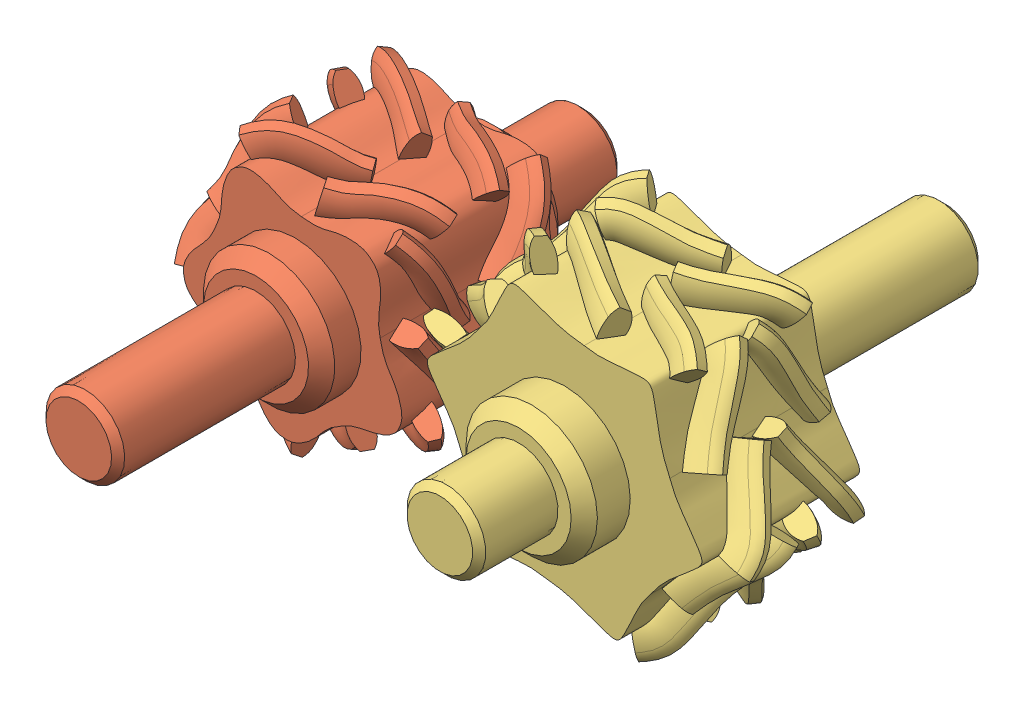
SolidWorks assembly Assme, configuration 默认. Lengths in mm.
Overall size (50.88 34.11 46).
4 component instances, 3 part files, 6 mates.
Components (placement in the parent):
- shaft-1: shaft [默认] at origin size (3 3 4)
- shaft-2: shaft [默认] at (20 0 0) size (3 3 4)
- drivingLG-1: drivingLG [默认] x (-0.673225 -0.739438 0) z (0 0 -1) size (20.19 20.72 38.5)
- drivenLG-1: drivenLG [默认] at (20 0 0) x (-0.787371 0.616479 0) z (0 0 -1) size (22.85 25.43 38.5)
Mates (geometry in assembly coordinates):
- 重合2: coincident: plane of shaft-1 through (0 0 0) normal (0 0 1); plane of assembly through (0 0 0) normal (0 0 1)
- 重合3: coincident: plane of shaft-1 through (0 0 0) normal (0 1 0); plane of assembly through (0 0 0) normal (0 1 0)
- 重合4: coincident: plane of shaft-1 through (0 0 0) normal (1 0 0); plane of assembly through (0 0 0) normal (1 0 0)
- 重合5: coincident: plane of shaft-1 through (0 0 0) normal (0 0 1); plane of shaft-2 through (20 0 0) normal (0 0 1)
- 重合6: coincident: plane of shaft-1 through (0 0 0) normal (0 1 0); plane of shaft-2 through (20 0 0) normal (0 1 0)
- 距离2: distance = 20 mm: plane of shaft-1 through (0 0 0) normal (1 0 0); plane of shaft-2 through (20 0 0) normal (1 0 0)
